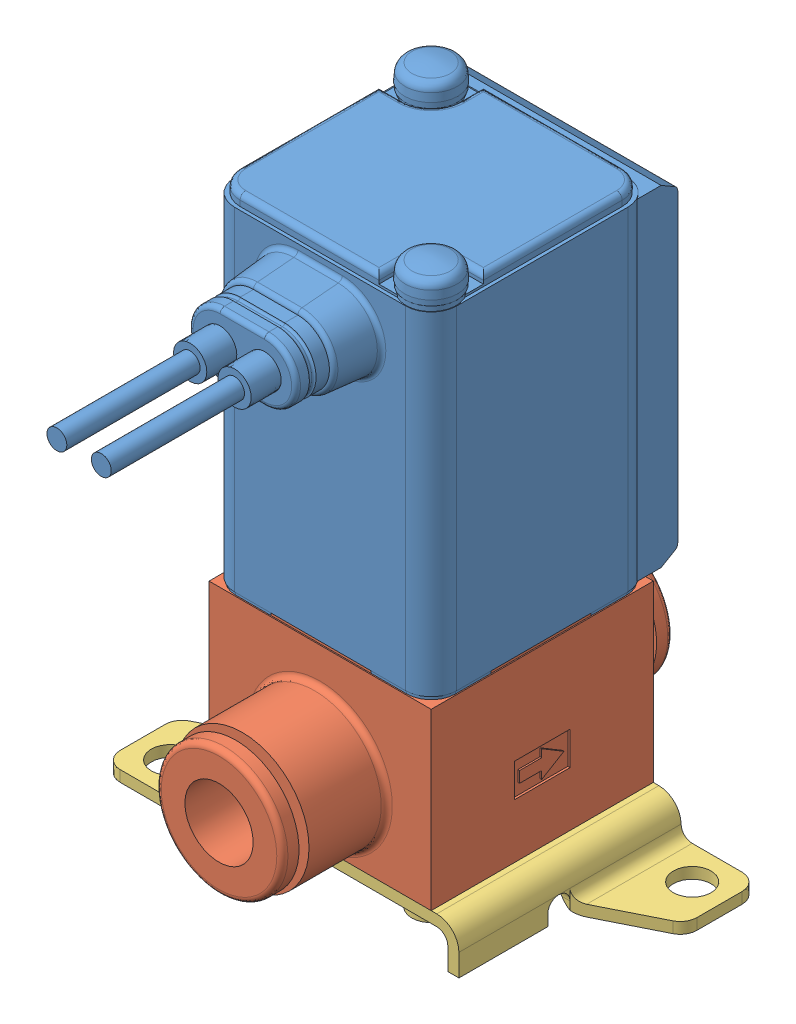
SolidWorks assembly VDW20GA, configuration VDW20GA. Lengths in mm.
Overall size (39 52.71 47.8).
3 component instances, 3 part files, 9 mates.
Components (placement in the parent):
- VDW20GA_VDW Grommet Block-1: VDW20GA_VDW Grommet Block [Default] at (0 20 0) size (20.31 33.01 44.2)
- VDW20GA_VDW Body Resin-1: VDW20GA_VDW Body Resin [OT6] at (0 10.4 0) size (20 16 35.2)
- VDW20GA_VDW Bracket for Resin Body-1: VDW20GA_VDW Bracket for Resin Body [Default] at (0 4 0) size (39 4 20)
Mates (geometry in assembly coordinates):
- Coincident1: coincident aligned: plane of VDW20GA_VDW Grommet Block-1 through (0 20 0.9808) normal (1 0 0); plane of VDW20GA_VDW Body Resin-1 through (0 10.4 0.9808) normal (1 0 0)
- Coincident2: coincident aligned: plane of VDW20GA_VDW Grommet Block-1 through (0 20 0.9808) normal (0 0 1); plane of VDW20GA_VDW Body Resin-1 through (0 10.4 0.9808) normal (0 0 1)
- Coincident3: coincident anti-aligned: plane of VDW20GA_VDW Grommet Block-1 through (-7.7 19.7 8.6808) normal (0 -1 0); plane of VDW20GA_VDW Body Resin-1 through (-10 19.7 10.9808) normal (0 1 0)
- Coincident13: coincident anti-aligned: plane of VDW20GA_VDW Body Resin-1 through (-10 4 10.9808) normal (0 -1 0); plane of VDW20GA_VDW Bracket for Resin Body-1 through (-12.5 4 10.9808) normal (0 1 0)
- Coincident14: coincident aligned: plane of VDW20GA_VDW Body Resin-1 through (0 10.4 0.9808) normal (0 0 1); plane of VDW20GA_VDW Bracket for Resin Body-1 through (0 4 0.9808) normal (0 0 1)
- Coincident15: coincident aligned: plane of VDW20GA_VDW Body Resin-1 through (0 10.4 0.9808) normal (1 0 0); plane of VDW20GA_VDW Bracket for Resin Body-1 through (0 4 0.9808) normal (1 0 0)
- Coincident16: coincident anti-aligned: plane of VDW20GA_VDW Bracket for Resin Body-1 through (-11.5 0 10.9808) normal (0 -1 0)
- Coincident17: coincident aligned: plane of VDW20GA_VDW Grommet Block-1 through (0 20 0.9808) normal (1 0 0)
- Coincident18: coincident aligned: plane of VDW20GA_VDW Grommet Block-1 through (0 20 0) normal (0 0 1)
